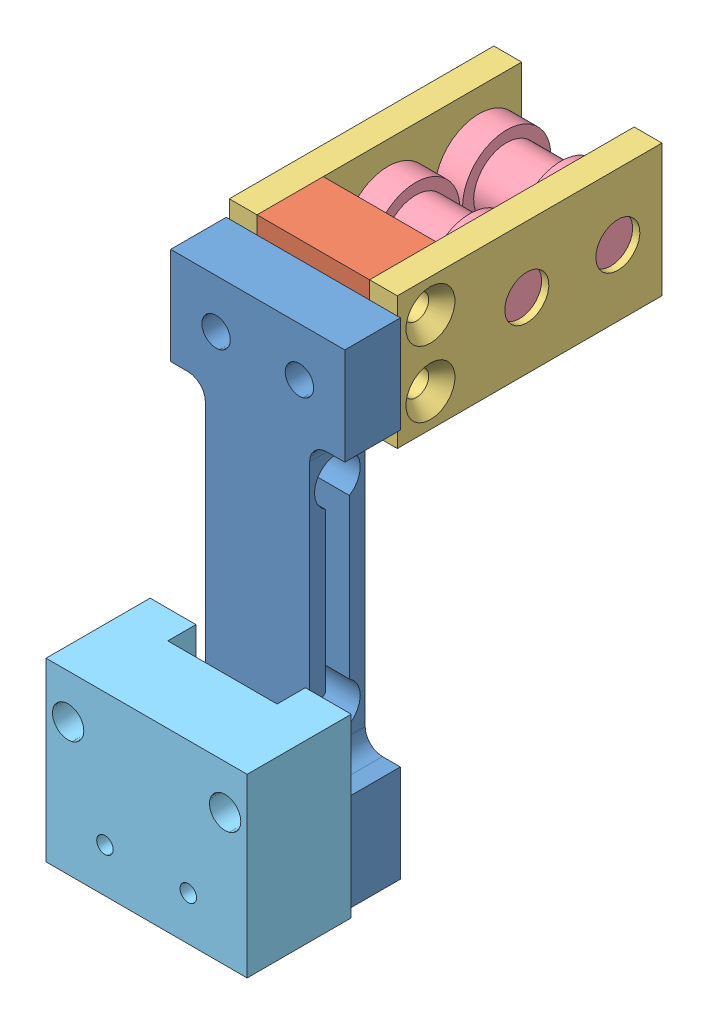
SolidWorks assembly vertical_load_cell, configuration Default. Lengths in mm.
Overall size (14.48 36.26 31.43).
7 component instances, 5 part files, 16 mates.
Components (placement in the parent):
- 100g_load_cell_RB-Phi-203-1: 100g_load_cell_RB-Phi-203 [Default] at (1.971 -4.5452 -9.8726) size (12.54 35 4)
- load_cell_vertical_adapter-1: load_cell_vertical_adapter [Default] at (-1.7598 26.9548 -14.6351) x (1 0 0) z (0 -1 0) size (8.1 4.76 9.53)
- load_cell_plate-1: load_cell_plate [Default] at (2.2902 26.9548 -19.3976) x (0 -1 0) z (1 0 0) size (9.53 19.05 2)
- load_cell_plate-2: load_cell_plate [Default] at (-5.8098 26.9548 -19.3976) x (0 1 0) z (-1 0 0) size (9.53 19.05 2)
- idle_roller_p25in-1: idle_roller_p25in [Default] at (-1.7598 26.9548 -25.7476) x (1 0 0) z (0 0.127055 -0.991896) size (11.07 6.35 6.35)
- idle_roller_p25in-2: idle_roller_p25in [Default] at (-1.7598 26.9548 -19.1944) x (1 0 0) z (0 -0.060789 0.998151) size (11.07 6.35 6.35)
- load_cell_vertical_base-1: load_cell_vertical_base [Default] at (-1.7598 2.1298 2.1284) x (1 0 0) z (0 1 0) size (14.48 7.49 12.7)
Mates (geometry in assembly coordinates):
- Concentric1: concentric: cylinder of 100g_load_cell_RB-Phi-203-1 through (1.2402 26.9548 -5.8726) axis (0 0 1) radius 1.025; cylinder of load_cell_vertical_adapter-1 through (1.2402 26.9548 -14.6351) axis (0 0 -1) radius 0.5956
- Concentric2: concentric: cylinder of 100g_load_cell_RB-Phi-203-1 through (-4.7598 26.9548 -5.8726) axis (0 0 1) radius 1.025; cylinder of load_cell_vertical_adapter-1 through (-4.7598 26.9548 -14.6351) axis (0 0 -1) radius 0.5956
- Coincident1: coincident: plane of 100g_load_cell_RB-Phi-203-1 through (-8.029 30.4548 -9.8726) normal (0 0 -1); plane of load_cell_vertical_adapter-1 through (2.2902 31.7173 -9.8726) normal (0 0 1)
- Coincident2: coincident: plane of load_cell_vertical_adapter-1 through (2.2902 22.1923 -9.8726) normal (1 0 0); plane of load_cell_plate-1 through (2.2902 22.1923 -28.9226) normal (-1 0 0)
- Concentric3: concentric: cylinder of load_cell_vertical_adapter-1 through (-5.8098 29.336 -12.2539) axis (-1 0 0) radius 0.5956; cylinder of load_cell_plate-1 through (4.2902 29.336 -12.2539) axis (1 0 0) radius 0.889
- Concentric4: concentric: cylinder of load_cell_vertical_adapter-1 through (-5.8098 24.5735 -12.2539) axis (-1 0 0) radius 0.5956; circle of load_cell_plate-1
- Coincident3: coincident: plane of load_cell_vertical_adapter-1 through (-5.8098 22.1923 -9.8726) normal (-1 0 0); plane of load_cell_plate-2 through (-5.8098 31.7173 -28.9226) normal (1 0 0)
- Concentric5: concentric: cylinder of load_cell_vertical_adapter-1 through (-5.8098 29.336 -12.2539) axis (-1 0 0) radius 0.5956; cylinder of load_cell_plate-2 through (-7.8098 29.336 -12.2539) axis (-1 0 0) radius 0.889
- Concentric6: concentric: cylinder of load_cell_vertical_adapter-1 through (-5.8098 24.5735 -12.2539) axis (-1 0 0) radius 0.5956; cylinder of load_cell_plate-2 through (-7.8098 24.5735 -12.2539) axis (-1 0 0) radius 0.889
- Concentric7: concentric: cylinder of load_cell_plate-1 through (4.2902 26.9548 -25.7476) axis (1 0 0) radius 1.5875; cylinder of idle_roller_p25in-1 through (10.0378 26.9548 -25.7476) axis (1 0 0) radius 1.5811
- Concentric8: concentric: cylinder of load_cell_plate-1 through (4.2902 26.9548 -19.1944) axis (1 0 0) radius 1.5875; cylinder of idle_roller_p25in-2 through (10.0378 26.9548 -19.1944) axis (1 0 0) radius 1.5811
- Width1: width: plane of load_cell_plate-2 through (-5.8098 31.7173 -28.9226) normal (1 0 0); plane of load_cell_plate-1 through (2.2902 22.1923 -28.9226) normal (-1 0 0); plane of idle_roller_p25in-1 through (-5.7098 25.3864 -25.9485) normal (-1 0 0); plane of idle_roller_p25in-1 through (2.1902 25.3864 -25.9485) normal (1 0 0)
- Width2: width: plane of load_cell_plate-2 through (-5.8098 31.7173 -28.9226) normal (1 0 0); plane of load_cell_plate-1 through (2.2902 22.1923 -28.9226) normal (-1 0 0); plane of idle_roller_p25in-2 through (-5.7098 28.533 -19.0983) normal (-1 0 0); plane of idle_roller_p25in-2 through (2.1902 28.533 -19.0983) normal (1 0 0)
- Concentric10: concentric: cylinder of 100g_load_cell_RB-Phi-203-1 through (-4.7598 -1.0452 -5.8726) axis (0 0 1) radius 1.025; cylinder of load_cell_vertical_base-1 through (-4.7598 -1.0452 -5.3646) axis (0 0 -1) radius 0.5956
- Concentric11: concentric: cylinder of 100g_load_cell_RB-Phi-203-1 through (1.2402 -1.0452 -5.8726) axis (0 0 1) radius 1.025; cylinder of load_cell_vertical_base-1 through (1.2402 -1.0452 -5.3646) axis (0 0 -1) radius 0.5956
- Distance1: distance = 0.508 mm: plane of 100g_load_cell_RB-Phi-203-1 through (-8.029 30.4548 -5.8726) normal (0 0 1); plane of load_cell_vertical_base-1 through (5.4792 -4.2202 -5.3646) normal (0 0 -1)
